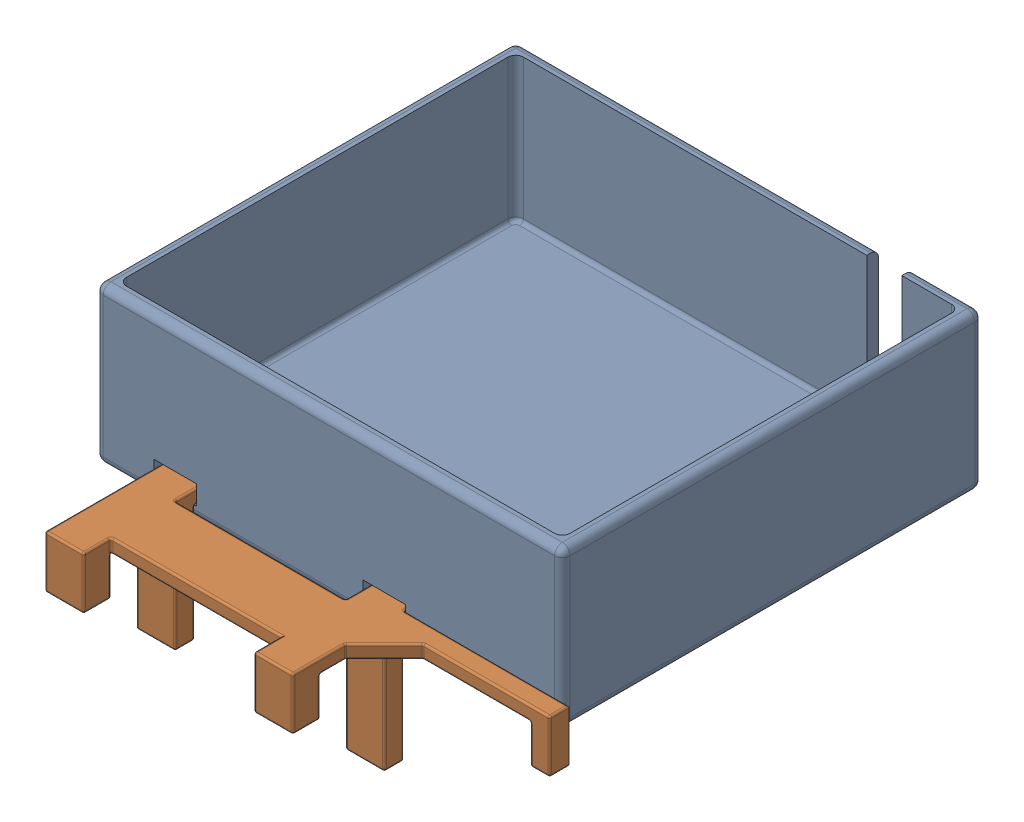
SolidWorks assembly Bin Clip_ASM, configuration Default. Lengths in mm.
Overall size (106.25 33.5 49).
3 component instances, 3 part files, 5 mates.
Components (placement in the parent):
- Bin sans feet-1: Bin sans feet [Default] at (17.9206 16.9349 64.6994) size (120 40 108) (hidden)
- 5537T711_200-1: 5537T711_200 [5537T711] at (-8.8739 -0.0651 143.6994) x (0 0 -1) z (1 0 0) (suppressed, hidden)
- Bin Clips 2-1: Bin Clips 2 [Default] at (-16.5794 19.0318 141.3443) x (0 0 1) z (-1 0 0) size (49 33.5 106.25)
Mates (geometry in assembly coordinates):
- Width1: width anti-aligned: plane of Bin sans feet-1 through (37.6706 19.9349 108.6994) normal (-1 0 0); plane of Bin Clips 2-1 through (-27.0794 19.9349 108.6994) normal (1 0 0); plane of Bin sans feet-1 through (-26.5794 19.0318 141.3443) normal (-1 0 0); plane of Bin Clips 2-1 through (37.1706 19.0318 141.3443) normal (1 0 0)
- Coincident1: coincident anti-aligned: plane of Bin sans feet-1 through (-42.0794 56.9349 118.6994) normal (0 0 1); plane of Bin Clips 2-1 through (37.1706 -10.0651 118.6994) normal (0 0 -1)
- Coincident2: coincident anti-aligned: plane of Bin sans feet-1 through (17.9206 19.9349 64.6994) normal (0 1 0); plane of Bin Clips 2-1 through (37.1706 19.9349 118.6994) normal (0 -1 0)
- Width2: width anti-aligned: plane of 5537T711_200-1 through (91.1261 16.1256 139.6994) normal (0 0 1); plane of Bin Clips 2-1 through (91.1261 16.1256 147.6994) normal (0 0 -1); plane of 5537T711_200-1 through (37.1706 19.9349 140.1994) normal (0 0 -1); plane of Bin Clips 2-1 through (37.1706 9.9349 147.1994) normal (0 0 1)
- Coincident3: coincident anti-aligned: plane of 5537T711_200-1 through (91.1261 19.9349 138.8994) normal (0 1 0); plane of Bin Clips 2-1 through (79.6706 19.9349 123.6994) normal (0 -1 0)
